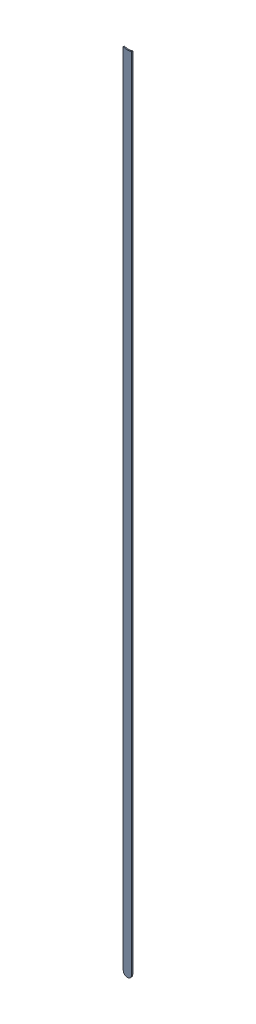
SolidWorks assembly Track (21.9mm,15.3mm)(21.9mm,40mm) on Bottom Layer, configuration Predeterminado. Lengths in mm.
Overall size (0.25 24.49 0.04).
2 component instances, 1 part files, 0 mates.
Components (placement in the parent):
- Track (21.9mm,15.3mm)(21.9mm,40mm) on Bottom Layer-1-1: Track (21.9mm,15.3mm)(21.9mm,40mm) on Bottom Layer-1 [Predeterminado] at (-68.317 -44.187 -0.4013) size (0.25 24.49 0.04)
  - Track (21.9mm,15.3mm)(21.9mm,40mm) on Bottom Layer-Part-1-1: Track (21.9mm,15.3mm)(21.9mm,40mm) on Bottom Layer-Part-1 [Predeterminado] at origin size (0.25 24.49 0.04)
